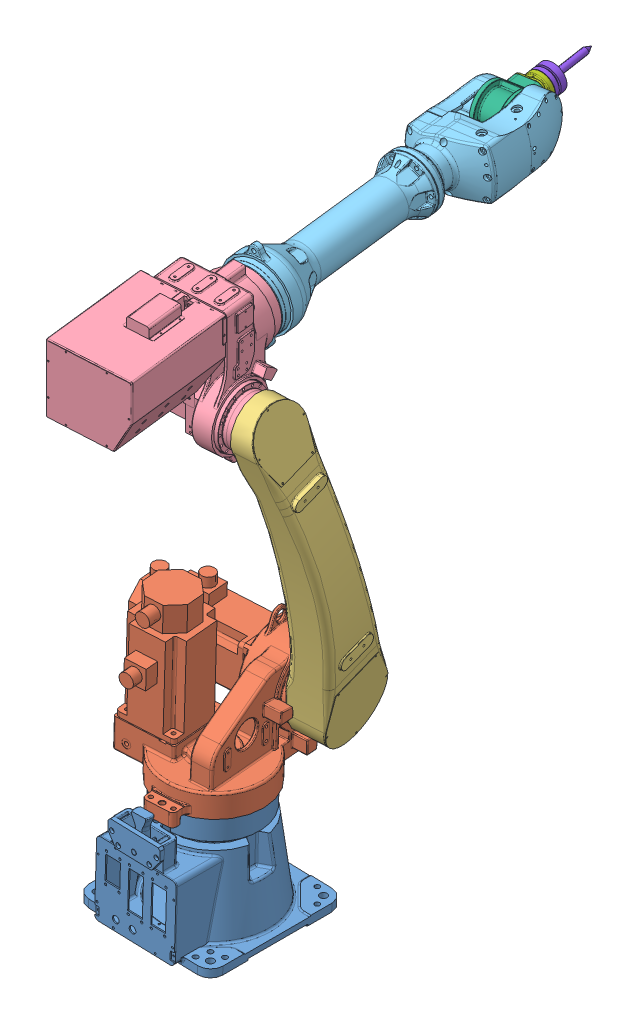
SolidWorks assembly ER16, configuration Default. Lengths in mm.
Overall size (557.53 1346.72 1318.29).
9 component instances, 9 part files, 18 mates.
Components (placement in the parent):
- ER16_base-1: ER16_base [Default] at (-343.6986 30.3208 0) x (0.99955 -0.029989 0) z (0 0 1) size (426.79 329 350.04)
- ER16_j1-1: ER16_j1 [默认] at (-343.6986 30.3208 0) x (0.99591 -0.02988 -0.085267) z (0.085229 -0.002557 0.996358) size (464.73 370.5 397)
- ER16_j2-1: ER16_j2 [默认] at (-378.7458 3.1209 -118.3482) x (0.99591 -0.02988 -0.085267) z (0.073533 -0.280313 0.957088) size (129.48 830.1 170.44)
- ER16_j3-1: ER16_j3 [默认] at (-355.6606 -1.0082 152.7323) x (0.99591 -0.02988 -0.085267) z (0.084143 -0.03706 0.995764) size (324.5 366.09 425)
- ER16_j4-1: ER16_j4 [默认] at (-241.9604 2.8445 97.5744) x (0.994443 0.066569 -0.081553) z (0.084143 -0.03706 0.995764) size (189.08 215.2 783.97)
- ER16_j5-1: ER16_j5 [默认] at (-244.7499 -28.5082 50.2292) x (0.994443 0.066569 -0.081553) z (0.086444 -0.074228 0.993488) size (86.5 170.25 120.5)
- ER16_j6-1: ER16_j6 [默认] at (-469.8154 2395.5348 250.9245) x (-0.988498 -0.130607 0.076252) z (0.086444 -0.074228 0.993488) size (69 69 63)
- Floor-1: Floor [默认] at (-344.2983 10.3298 0) x (0.9992 -0.029978 0.026484) z (-0.026472 0.000794 0.999649) size (1000 20 1000) (hidden)
- Tool-1: Tool [默认] at (-405.0457 1262.002 -850.9908) x (0.963309 -0.248113 -0.102356) z (0.254094 0.965883 0.050057) size (63 132.52 63)
Mates (geometry in assembly coordinates):
- 重合2: coincident anti-aligned: plane of ER16_base-1 through (-257.6509 299.8615 -136.9169) normal (0.029989 0.99955 0); plane of ER16_j1-1 through (-437.8402 305.2676 121.5011) normal (-0.029989 -0.99955 0)
- 同心1: concentric aligned: cylinder of ER16_base-1 through (-333.8472 358.673 0) axis (-0.029989 -0.99955 0) radius 25.5; circle of ER16_j1-1
- 重合3: coincident anti-aligned: plane of ER16_j1-1 through (-248.933 544.4466 -210.9135) normal (0.99591 -0.02988 -0.085267); plane of ER16_j2-1 through (-257.2408 391.8803 -254.4844) normal (-0.99591 0.02988 0.085267)
- 同心2: concentric aligned: circle of ER16_j1-1; circle of ER16_j2-1
- 重合6: coincident anti-aligned: plane of ER16_j3-1 through (-216.2758 1094.4703 -45.6775) normal (0.99591 -0.02988 -0.085267); plane of ER16_j2-1 through (-215.953 1063.6234 -31.0978) normal (-0.99591 0.02988 0.085267)
- 同心3: concentric aligned: circle of ER16_j2-1; circle of ER16_j3-1
- 重合7: coincident anti-aligned: plane of ER16_j3-1 through (-268.6822 1154.6522 -96.8149) normal (-0.084143 0.03706 -0.995764); plane of ER16_j4-1 through (-407.2586 1152.5466 -85.1834) normal (0.084143 -0.03706 0.995764)
- 同心5: concentric aligned: circle of ER16_j3-1; circle of ER16_j4-1
- 同心6: concentric anti-aligned: cone of ER16_j4-1 through (-432.4288 1252.5676 -753.6904) axis (-0.994443 -0.066569 0.081553); circle of ER16_j5-1
- 重合9: coincident anti-aligned: plane of ER16_j5-1 through (-438.8335 1291.8066 -815.6274) normal (-0.086444 0.074228 -0.993488); plane of ER16_j6-1 through (-364.0679 1230.1726 -826.7378) normal (0.086444 -0.074228 0.993488)
- 同心7: concentric aligned: circle of ER16_j5-1; circle of ER16_j6-1
- 重合12: coincident anti-aligned: plane of ER16_j4-1 through (-423.8265 1197.9781 -703.093) normal (0.994443 0.066569 -0.081553); plane of ER16_j5-1 through (-439.4239 1309.4294 -802.3116) normal (-0.994443 -0.066569 0.081553)
- 同心10: concentric aligned: circle of ER16_j6-1; circle of Tool-1
- 重合14: coincident anti-aligned: plane of ER16_j6-1 through (-378.3651 1296.5491 -850.7312) normal (-0.086444 0.074228 -0.993488); plane of Tool-1 through (-405.0457 1262.002 -850.9908) normal (0.086444 -0.074228 0.993488)
- 同心11: concentric anti-aligned: circle of ER16_base-1; circle of Floor-1
- 重合15: coincident anti-aligned: plane of ER16_base-1 through (-503.6266 35.119 70) normal (-0.029989 -0.99955 0); plane of Floor-1 through (-343.6986 30.3208 0) normal (0.029989 0.99955 0)
- 重合16: coincident: plane of Floor-1 through (-344.2983 10.3298 0) normal (-0.029989 -0.99955 0)
- 重合17: coincident aligned: plane of ER16_base-1 through (-343.6986 30.3208 0) normal (0 0 1)
